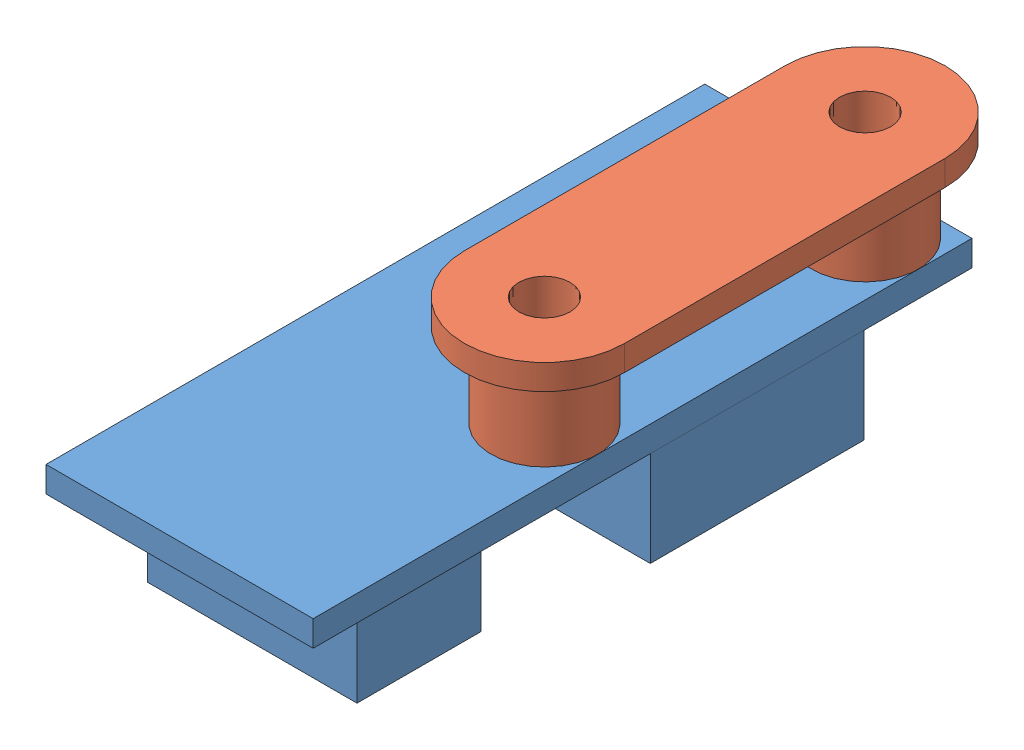
SolidWorks assembly 3-Limit-switch-assembly, configuration Default. Lengths in mm.
Overall size (17.46 13.87 40.73).
2 component instances, 2 part files, 2 mates.
Components (placement in the parent):
- 3-limit-switch-1: 3-limit-switch [Default] at (-142.3296 38.9472 52.7664) size (15.88 7.37 39.14)
- 3-Limit-switch-mount-1: 3-Limit-switch-mount [Default] at (-132.8046 45.4712 52.7664) x (-1 0 0) z (0 1 0) size (9.53 28.57 6.5)
Mates (geometry in assembly coordinates):
- Concentric1: concentric: circle of assembly; cylinder of assembly; circle of 3-limit-switch-1; cylinder of 3-Limit-switch-mount-1 through (-137.5671 46.9712 52.7664) axis (0 -1 0) radius 1.524
- Coincident2: coincident: plane of assembly; plane of assembly; plane of 3-limit-switch-1 through (-142.3296 40.4712 52.7664) normal (0 1 0); plane of 3-Limit-switch-mount-1 through (-132.8046 40.4712 52.7664) normal (0 -1 0)
